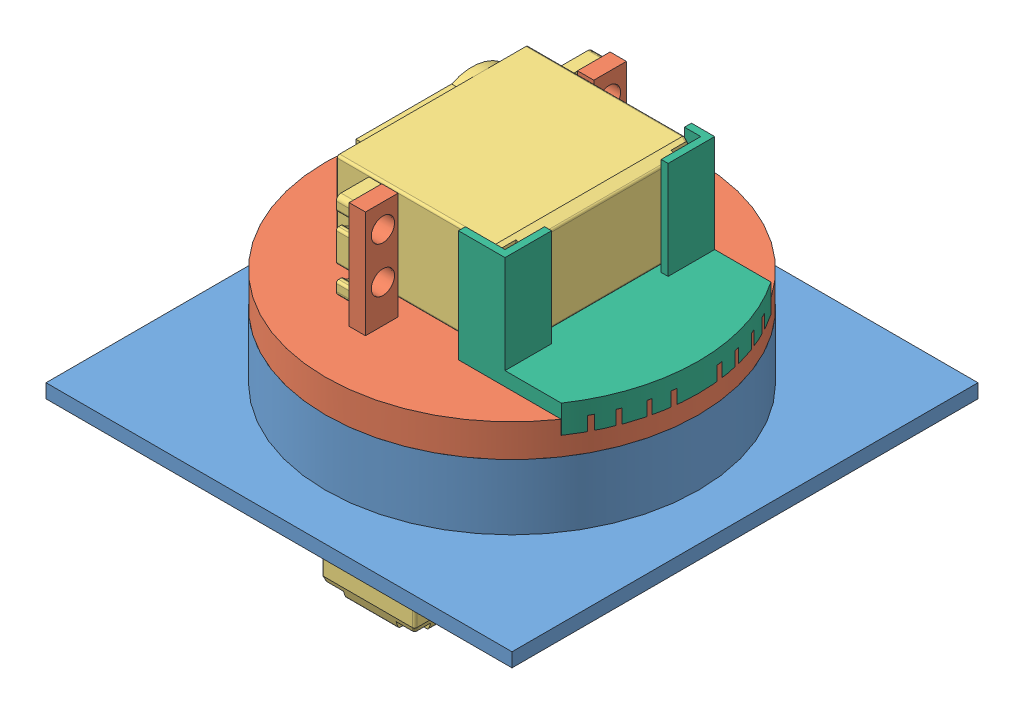
SolidWorks assembly PanAndTilt1, configuration Default. Lengths in mm.
Overall size (100 72.8 100).
10 component instances, 6 part files, 17 mates.
Components (placement in the parent):
- basePanTilt-1: basePanTilt [Default] at (34.1107 41.4873 83.0065) size (100 17 100)
- Part2^PanAndTilt1-1: Part2^PanAndTilt1 [Default] at (34.1107 47.9873 83.0065) x (1 0 0) z (0 1 0) size (80 80 30) (virtual)
- MG996R-ServoMotor-3: MG996R-ServoMotor [Default] at (18.8732 2.3088 49.9532) size (20 44.02 55)
  - MG996R-ServoMotor-1: MG996R-ServoMotor [Default] at (5.2376 21.8785 43.4533) size (20 40 55)
  - MG996R-Gear-1: MG996R-Gear [Default] at (5.3909 -12.8534 33.0533) size (6 6.02 6)
- Horn-1: Horn [Default] at (44.1319 52.8373 133.626) x (0.837169 0 0.546944) z (0.546944 0 -0.837169) size (36 6.5 36)
- MG996R-ServoMotor-7: MG996R-ServoMotor [Default] at (56.9892 52.7497 39.5532) x (0 1 0) z (0 0 1) size (20 44.02 55)
  - MG996R-ServoMotor-1: MG996R-ServoMotor [Default] at (5.2376 21.8785 43.4533) size (20 40 55)
  - MG996R-Gear-1: MG996R-Gear [Default] at (5.3909 -12.8534 33.0533) size (6 6.02 6)
- Part3^PanAndTilt1-1: Part3^PanAndTilt1 [Default] at (0 54.9873 0) x (1 0 0) z (0 1 0) size (29 45 27) (virtual)
Mates (geometry in assembly coordinates):
- InPlace1: in place: plane of basePanTilt-1 through (34.1107 49.4873 83.0065) normal (0 1 0); plane of ? through (0 49.4873 0) normal (0 1 0); moOrthogonalPlaneRef_w of basePanTilt-1 through (34.1107 49.4873 83.0065) normal (0 1 0); plane of ? through (0 49.4873 0) normal (0 0 -1); plane of basePanTilt-1 through (34.1107 49.4873 83.0065) normal (0 1 0); line of ? through (-55 0 49.4873) axis (0 1 0); plane of basePanTilt-1 through (34.1107 47.9873 83.0065) normal (0 1 0); unknown of Part2^PanAndTilt1-1
- Coincident1: coincident aligned: plane of basePanTilt-1; plane of Part2^PanAndTilt1-1
- Coincident2: coincident aligned: moOrthogonalPlaneRef_w of basePanTilt-1 through (34.1107 47.9873 83.0065) normal (0 0 -1); plane of Part2^PanAndTilt1-1 through (34.1107 47.9873 83.0065) normal (0 0 -1)
- Coincident3: coincident anti-aligned: moOrthogonalPlaneRef_w of basePanTilt-1 through (34.1107 47.9873 83.0065) normal (-1 0 0); plane of Part2^PanAndTilt1-1
- Concentric1: concentric anti-aligned: cylinder of basePanTilt-1 through (34.1107 47.9873 83.0065) axis (0 -1 0) radius 11.5; cylinder of MG996R-ServoMotor-3/MG996R-Gear-1 through (34.1107 42.1873 83.0065) axis (0 1 0) radius 1.5
- Coincident3: coincident anti-aligned: plane of basePanTilt-1 through (34.1107 42.1873 83.0065) normal (0 -1 0); plane of MG996R-ServoMotor-3/MG996R-ServoMotor-1 through (44.1107 42.1873 113.9065) normal (0 1 0)
- Parallel3: parallel aligned: plane of basePanTilt-1 through (23.1107 42.1873 71.9065) normal (1 0 0); plane of MG996R-ServoMotor-3/MG996R-ServoMotor-1 through (44.1107 24.1873 93.4065) normal (1 0 0)
- Concentric2: concentric aligned: cylinder of MG996R-ServoMotor-3/MG996R-Gear-1 through (34.1107 40.4873 83.0065) axis (0 1 0) radius 1.5; cylinder of ? through (34.1107 49.4873 83.0065) axis (0 1 0) radius 3
- Coincident5: coincident anti-aligned: plane of MG996R-ServoMotor-3/MG996R-Gear-1 through (37.1107 48.4873 83.0065) normal (0 1 0); plane of ? through (34.1107 48.4873 83.0065) normal (0 -1 0)
- Concentric3: concentric aligned: circle of MG996R-ServoMotor-3/MG996R-Gear-1; cylinder of Horn-1 through (34.1107 46.8373 83.0065) axis (0 1 0) radius 3
- Coincident6: coincident anti-aligned: plane of MG996R-ServoMotor-3/MG996R-Gear-1 through (37.1107 50.1873 83.0065) normal (0 1 0); plane of Horn-1 through (44.1319 50.1873 133.626) normal (0 -1 0)
- Coincident7: coincident anti-aligned: plane of Part2^PanAndTilt1-1 through (34.1107 54.9873 83.0065) normal (0 1 0); plane of ? through (31.9145 54.9873 81.5989) normal (0 -1 0)
- Parallel5: parallel aligned: plane of ? through (13.9145 54.9873 102.0989) normal (-1 0 0); plane of MG996R-ServoMotor-3/MG996R-ServoMotor-1 through (24.1107 21.9873 93.4065) normal (-1 0 0)
- Distance5: distance = 3 mm anti-aligned: plane of Part2^PanAndTilt1-1 through (34.1107 54.9873 83.0065) normal (0 1 0); plane of MG996R-ServoMotor-7/MG996R-ServoMotor-1 through (35.1107 57.9873 83.0065) normal (0 -1 0)
- Parallel6: parallel aligned: plane of MG996R-ServoMotor-3/MG996R-ServoMotor-1 through (44.1107 6.1873 72.9065) normal (0 0 -1); plane of MG996R-ServoMotor-7/MG996R-ServoMotor-1 through (53.1107 77.9873 62.5065) normal (0 0 -1)
- Distance3: distance = 29.5 mm aligned: plane of MG996R-ServoMotor-7/MG996R-ServoMotor-1 through (53.1107 77.9873 62.5065) normal (0 0 -1); plane of basePanTilt-1 through (84.1107 30.9873 33.0065) normal (0 0 -1)
- Distance4: distance = 31 mm aligned: plane of MG996R-ServoMotor-7/MG996R-ServoMotor-1 through (15.1107 57.9873 83.0065) normal (-1 0 0); plane of basePanTilt-1 through (-15.8893 30.9873 133.0065) normal (-1 0 0)
